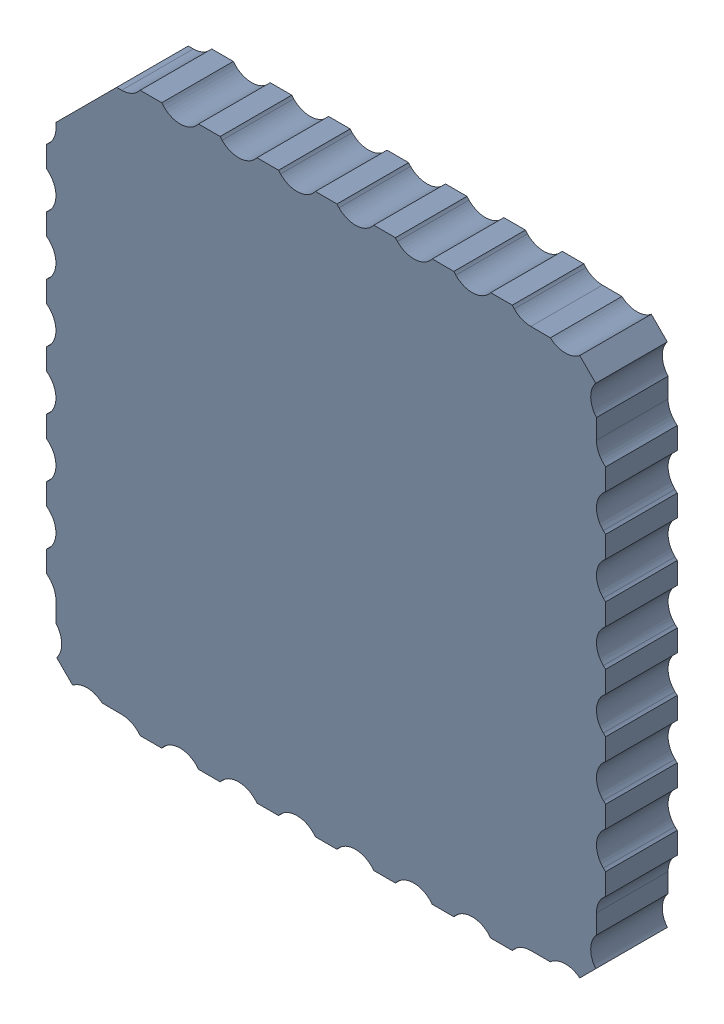
SolidWorks assembly Board_1v2(2)^MTi-1-SoB_v2, configuration Default. Lengths in mm.
Overall size (12.15 12.15 1.56).
2 component instances, 1 part files, 0 mates.
Components (placement in the parent):
- Open CASCADE STEP translator 6.8 2.1.1^Board_1v2(2)_MTi-1-SoB_v2-1: Open CASCADE STEP translator 6.8 2.1.1^Board_1v2(2)_MTi-1-SoB_v2 [Default] at (0 0 -1.5563) size (12.15 12.15 1.56)
  - Open CASCADE STEP translator 6.8 2.1.1.1^Open CASCADE STEP translator_ 6.8 2.1.1_Board_1v2(2)_MTi-1-SoB_v2-1: Open CASCADE STEP translator 6.8 2.1.1.1^Open CASCADE STEP translator_ 6.8 2.1.1_Board_1v2(2)_MTi-1-SoB_v2 [Default] at origin size (12.15 12.15 1.56)
